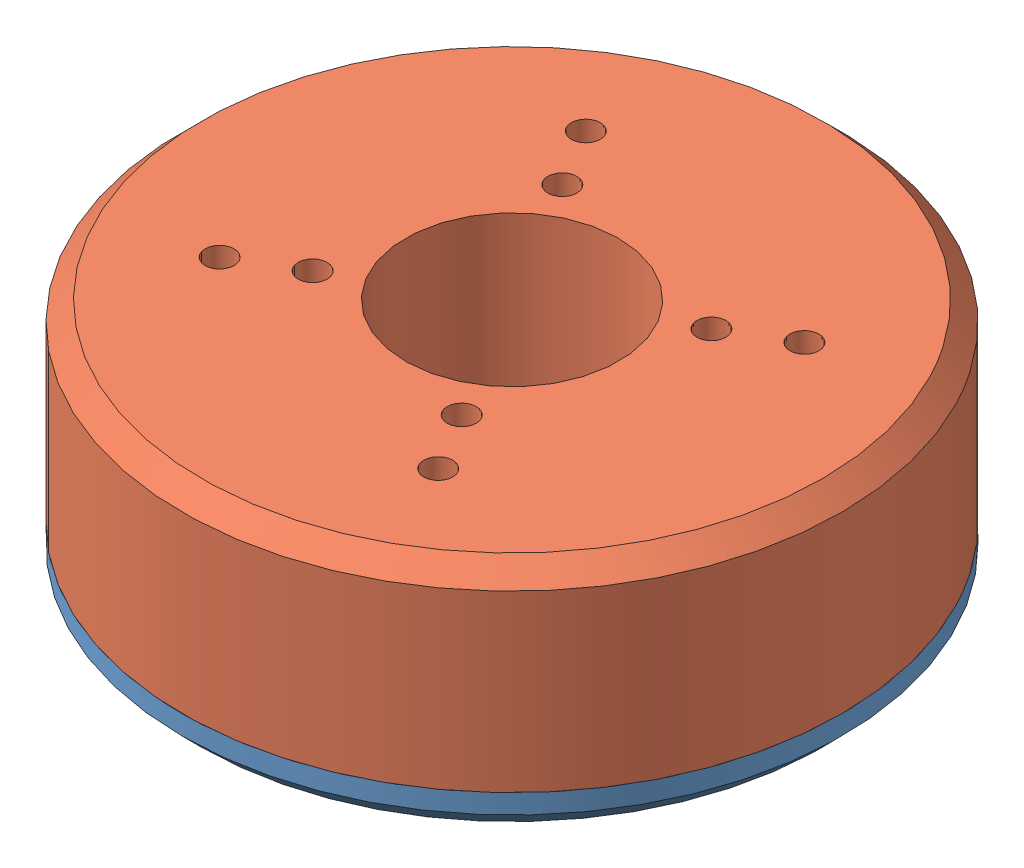
SolidWorks assembly 电机_驱动器, configuration 默认. Lengths in mm.
Overall size (93.24 25 93.24).
2 component instances, 2 part files, 5 mates.
Components (placement in the parent):
- 电机定子座-1: 电机定子座 [默认] at origin size (68 13 68)
- 电机外转子-1: 电机外转子 [默认] at (0 4 0) x (-0.512618 0 -0.858617) z (0.858617 0 -0.512618) size (68 20 68)
Mates (geometry in assembly coordinates):
- 重合1: coincident: plane of assembly through (0 0 0) normal (0 1 0); plane of 电机定子座-1 through (0 0 0) normal (0 1 0); plane of assembly
- 重合2: coincident: plane of assembly through (0 0 0) normal (0 0 1); plane of 电机定子座-1 through (0 0 0) normal (0 0 1); plane of assembly
- 重合3: coincident: plane of assembly through (0 0 0) normal (1 0 0); plane of 电机定子座-1 through (0 0 0) normal (1 0 0); plane of assembly
- 同心1: concentric: cylinder of assembly; cylinder of assembly; cylinder of 电机定子座-1 through (0 12 0) axis (0 -1 0) radius 30; cylinder of 电机外转子-1 through (0 24 0) axis (0 -1 0) radius 30
- 重合4: coincident: plane of assembly; plane of assembly; plane of 电机定子座-1 through (0 4 0) normal (0 1 0); plane of 电机外转子-1 through (0 4 0) normal (0 -1 0)
